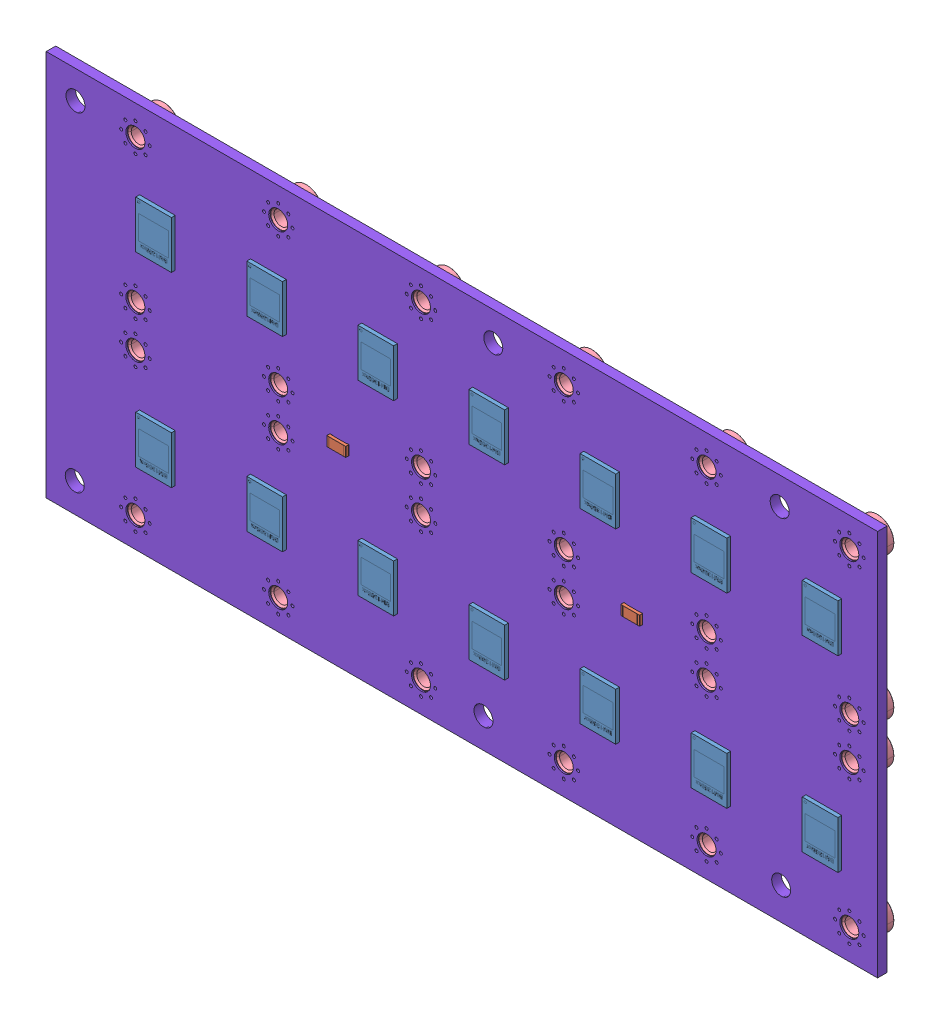
SolidWorks assembly EKO_Miner_AsicBoard-Template-01A, configuration Défaut. Lengths in mm.
Overall size (139.75 65 11.65).
104 component instances, 8 part files, 0 mates.
Components (placement in the parent):
- EKO_Miner_AsicBoard-Template-01A.step-1: EKO_Miner_AsicBoard-Template-01A.step [Défaut] at origin size (139.75 65 11.65)
  - BM1368xx.step-1: BM1368xx.step [Défaut] at (56.091 48.0498 1.65) x (-1 0 0) z (0 0 1) size (6 8 0.65)
    - BM1368PB.step-1: BM1368PB.step [Défaut] at origin size (6 8 0.65)
  - R_1206_3216Metric.step-1: R_1206_3216Metric.step [Défaut] at (49.348 32.465 1.65) size (3.2 1.6 0.55)
    - R_1206_3216Metric-0.step-1: R_1206_3216Metric-0.step [Défaut] at origin size (3.2 1.6 0.55)
  - BM1368xx.step-2: BM1368xx.step [Défaut] at (56.091 16.717 1.65) x (-1 0 0) z (0 0 1) size (6 8 0.65)
    - BM1368PB.step-1: BM1368PB.step [Défaut] at origin size (6 8 0.65)
  - BM1368xx.step-3: BM1368xx.step [Défaut] at (18.746 48.0498 1.65) x (-1 0 0) z (0 0 1) size (6 8 0.65)
    - BM1368PB.step-1: BM1368PB.step [Défaut] at origin size (6 8 0.65)
  - BM1368xx.step-4: BM1368xx.step [Défaut] at (93.436 16.717 1.65) x (-1 0 0) z (0 0 1) size (6 8 0.65)
    - BM1368PB.step-1: BM1368PB.step [Défaut] at origin size (6 8 0.65)
  - BM1368xx.step-5: BM1368xx.step [Défaut] at (93.436 48.0498 1.65) x (-1 0 0) z (0 0 1) size (6 8 0.65)
    - BM1368PB.step-1: BM1368PB.step [Défaut] at origin size (6 8 0.65)
  - BM1368xx.step-6: BM1368xx.step [Défaut] at (37.4185 48.0498 1.65) x (-1 0 0) z (0 0 1) size (6 8 0.65)
    - BM1368PB.step-1: BM1368PB.step [Défaut] at origin size (6 8 0.65)
  - BM1368xx.step-7: BM1368xx.step [Défaut] at (112.1085 48.0498 1.65) x (-1 0 0) z (0 0 1) size (6 8 0.65)
    - BM1368PB.step-1: BM1368PB.step [Défaut] at origin size (6 8 0.65)
  - BM1368xx.step-8: BM1368xx.step [Défaut] at (112.1085 16.717 1.65) x (-1 0 0) z (0 0 1) size (6 8 0.65)
    - BM1368PB.step-1: BM1368PB.step [Défaut] at origin size (6 8 0.65)
  - BM1368xx.step-9: BM1368xx.step [Défaut] at (74.7635 48.0498 1.65) x (-1 0 0) z (0 0 1) size (6 8 0.65)
    - BM1368PB.step-1: BM1368PB.step [Défaut] at origin size (6 8 0.65)
  - BM1368xx.step-10: BM1368xx.step [Défaut] at (37.4185 16.717 1.65) x (-1 0 0) z (0 0 1) size (6 8 0.65)
    - BM1368PB.step-1: BM1368PB.step [Défaut] at origin size (6 8 0.65)
  - BM1368xx.step-11: BM1368xx.step [Défaut] at (74.7635 16.717 1.65) x (-1 0 0) z (0 0 1) size (6 8 0.65)
    - BM1368PB.step-1: BM1368PB.step [Défaut] at origin size (6 8 0.65)
  - BM1368xx.step-12: BM1368xx.step [Défaut] at (18.746 16.717 1.65) x (-1 0 0) z (0 0 1) size (6 8 0.65)
    - BM1368PB.step-1: BM1368PB.step [Défaut] at origin size (6 8 0.65)
  - R_1206_3216Metric.step-2: R_1206_3216Metric.step [Défaut] at (98.751 32.592 1.65) size (3.2 1.6 0.55)
    - R_1206_3216Metric-0.step-1: R_1206_3216Metric-0.step [Défaut] at origin size (3.2 1.6 0.55)
  - BM1368xx.step-13: BM1368xx.step [Défaut] at (130.781 16.717 1.65) x (-1 0 0) z (0 0 1) size (6 8 0.65)
    - BM1368PB.step-1: BM1368PB.step [Défaut] at origin size (6 8 0.65)
  - BM1368xx.step-14: BM1368xx.step [Défaut] at (130.781 48.264 1.65) x (-1 0 0) z (0 0 1) size (6 8 0.65)
    - BM1368PB.step-1: BM1368PB.step [Défaut] at origin size (6 8 0.65)
  - C_0805_2012Metric.step-1: C_0805_2012Metric.step [Défaut] at (6.702 9.097 -0.05) x (-1 0 0) z (0 0 -1) size (2 1.25 1.25)
    - C_0805_2012Metric-0.step-1: C_0805_2012Metric-0.step [Défaut] at origin size (2 1.25 1.25)
  - SMTSO-M3-3ET.step-1: SMTSO-M3-3ET.step [Défaut] at (39 29 1.35) x (0 0 -1) z (1 0 0) size (4.53 5.56 5.56)
    - 1.step-1: 1.step [Défaut] at origin size (4.53 5.56 5.56)
  - SMTSO-M3-3ET.step-2: SMTSO-M3-3ET.step [Défaut] at (111 5 1.35) x (0 0 -1) z (1 0 0) size (4.53 5.56 5.56)
    - 1.step-1: 1.step [Défaut] at origin size (4.53 5.56 5.56)
  - SMTSO-M3-3ET.step-3: SMTSO-M3-3ET.step [Défaut] at (63 29 1.35) x (0 0 -1) z (1 0 0) size (4.53 5.56 5.56)
    - 1.step-1: 1.step [Défaut] at origin size (4.53 5.56 5.56)
  - SMTSO-M3-3ET.step-4: SMTSO-M3-3ET.step [Défaut] at (87 36 1.35) x (0 0 -1) z (1 0 0) size (4.53 5.56 5.56)
    - 1.step-1: 1.step [Défaut] at origin size (4.53 5.56 5.56)
  - SMTSO-M3-3ET.step-5: SMTSO-M3-3ET.step [Défaut] at (15 60 1.35) x (0 0 -1) z (1 0 0) size (4.53 5.56 5.56)
    - 1.step-1: 1.step [Défaut] at origin size (4.53 5.56 5.56)
  - PinHeader_2x04_P2.54mm_Vertical_SMD.step-1: PinHeader_2x04_P2.54mm_Vertical_SMD.step [Défaut] at (4.67 26.242 -0.05) x (1 0 0) z (0 0 -1) size (7.54 10.16 9.3)
    - PinHeader_2x04_P254mm_Vertical_SMD.step-1: PinHeader_2x04_P254mm_Vertical_SMD.step [Défaut] at origin size (7.54 10.16 9.3)
  - SMTSO-M3-3ET.step-6: SMTSO-M3-3ET.step [Défaut] at (135 5 1.35) x (0 0 -1) z (1 0 0) size (4.53 5.56 5.56)
    - 1.step-1: 1.step [Défaut] at origin size (4.53 5.56 5.56)
  - SMTSO-M3-3ET.step-7: SMTSO-M3-3ET.step [Défaut] at (63 60 1.35) x (0 0 -1) z (1 0 0) size (4.53 5.56 5.56)
    - 1.step-1: 1.step [Défaut] at origin size (4.53 5.56 5.56)
  - C_0805_2012Metric.step-2: C_0805_2012Metric.step [Défaut] at (6.829 55.6625 -0.05) x (-1 0 0) z (0 0 -1) size (2 1.25 1.25)
    - C_0805_2012Metric-0.step-1: C_0805_2012Metric-0.step [Défaut] at origin size (2 1.25 1.25)
  - SOT230P700X180-4N.step-1: SOT230P700X180-4N.step [Défaut] at (4.67 13.669 -0.05) x (-1 0 0) z (0 -1 0) size (7 1.8 6.5)
    - MIC39100-3.3WS-TR.step-1: MIC39100-3.3WS-TR.step [Défaut] at origin size (7 1.8 6.5)
  - SMTSO-M3-3ET.step-8: SMTSO-M3-3ET.step [Défaut] at (63 5 1.35) x (0 0 -1) z (1 0 0) size (4.53 5.56 5.56)
    - 1.step-1: 1.step [Défaut] at origin size (4.53 5.56 5.56)
  - R_0805_2012Metric.step-1: R_0805_2012Metric.step [Défaut] at (24.625 5.795 -0.05) x (-1 0 0) z (0 0 -1) size (2 1.2 0.45)
    - R_0805_2012Metric-3.step-1: R_0805_2012Metric-3.step [Défaut] at origin size (2 1.2 0.45)
  - SOT230P700X180-4N.step-2: SOT230P700X180-4N.step [Défaut] at (4.67 51.134 -0.05) x (-1 0 0) z (0 -1 0) size (7 1.8 6.5)
    - MIC39100-3.3WS-TR.step-1: MIC39100-3.3WS-TR.step [Défaut] at origin size (7 1.8 6.5)
  - SMTSO-M3-3ET.step-9: SMTSO-M3-3ET.step [Défaut] at (39 5 1.35) x (0 0 -1) z (1 0 0) size (4.53 5.56 5.56)
    - 1.step-1: 1.step [Défaut] at origin size (4.53 5.56 5.56)
  - SMTSO-M3-3ET.step-10: SMTSO-M3-3ET.step [Défaut] at (87 5 1.35) x (0 0 -1) z (1 0 0) size (4.53 5.56 5.56)
    - 1.step-1: 1.step [Défaut] at origin size (4.53 5.56 5.56)
  - SMTSO-M3-3ET.step-11: SMTSO-M3-3ET.step [Défaut] at (87 29 1.35) x (0 0 -1) z (1 0 0) size (4.53 5.56 5.56)
    - 1.step-1: 1.step [Défaut] at origin size (4.53 5.56 5.56)
  - C_0805_2012Metric.step-3: C_0805_2012Metric.step [Défaut] at (6.829 46.6455 -0.05) x (-1 0 0) z (0 0 -1) size (2 1.25 1.25)
    - C_0805_2012Metric-0.step-1: C_0805_2012Metric-0.step [Défaut] at origin size (2 1.25 1.25)
  - SMTSO-M3-3ET.step-12: SMTSO-M3-3ET.step [Défaut] at (111 36 1.35) x (0 0 -1) z (1 0 0) size (4.53 5.56 5.56)
    - 1.step-1: 1.step [Défaut] at origin size (4.53 5.56 5.56)
  - PinHeader_2x04_P2.54mm_Vertical_SMD.step-2: PinHeader_2x04_P2.54mm_Vertical_SMD.step [Défaut] at (4.67 39.958 -0.05) x (1 0 0) z (0 0 -1) size (7.54 10.16 9.3)
    - PinHeader_2x04_P254mm_Vertical_SMD.step-1: PinHeader_2x04_P254mm_Vertical_SMD.step [Défaut] at origin size (7.54 10.16 9.3)
  - SMTSO-M3-3ET.step-13: SMTSO-M3-3ET.step [Défaut] at (135 29 1.35) x (0 0 -1) z (1 0 0) size (4.53 5.56 5.56)
    - 1.step-1: 1.step [Défaut] at origin size (4.53 5.56 5.56)
  - SMTSO-M3-3ET.step-14: SMTSO-M3-3ET.step [Défaut] at (111 60 1.35) x (0 0 -1) z (1 0 0) size (4.53 5.56 5.56)
    - 1.step-1: 1.step [Défaut] at origin size (4.53 5.56 5.56)
  - R_0805_2012Metric.step-2: R_0805_2012Metric.step [Défaut] at (24.641 3.382 -0.05) x (-1 0 0) z (0 0 -1) size (2 1.2 0.45)
    - R_0805_2012Metric-3.step-1: R_0805_2012Metric-3.step [Défaut] at origin size (2 1.2 0.45)
  - SMTSO-M3-3ET.step-15: SMTSO-M3-3ET.step [Défaut] at (39 60 1.35) x (0 0 -1) z (1 0 0) size (4.53 5.56 5.56)
    - 1.step-1: 1.step [Défaut] at origin size (4.53 5.56 5.56)
  - SMTSO-M3-3ET.step-16: SMTSO-M3-3ET.step [Défaut] at (135 60 1.35) x (0 0 -1) z (1 0 0) size (4.53 5.56 5.56)
    - 1.step-1: 1.step [Défaut] at origin size (4.53 5.56 5.56)
  - SMTSO-M3-3ET.step-17: SMTSO-M3-3ET.step [Défaut] at (39 36 1.35) x (0 0 -1) z (1 0 0) size (4.53 5.56 5.56)
    - 1.step-1: 1.step [Défaut] at origin size (4.53 5.56 5.56)
  - SMTSO-M3-3ET.step-18: SMTSO-M3-3ET.step [Défaut] at (63 36 1.35) x (0 0 -1) z (1 0 0) size (4.53 5.56 5.56)
    - 1.step-1: 1.step [Défaut] at origin size (4.53 5.56 5.56)
  - SMTSO-M3-3ET.step-19: SMTSO-M3-3ET.step [Défaut] at (135 36 1.35) x (0 0 -1) z (1 0 0) size (4.53 5.56 5.56)
    - 1.step-1: 1.step [Défaut] at origin size (4.53 5.56 5.56)
  - SMTSO-M3-3ET.step-20: SMTSO-M3-3ET.step [Défaut] at (111 29 1.35) x (0 0 -1) z (1 0 0) size (4.53 5.56 5.56)
    - 1.step-1: 1.step [Défaut] at origin size (4.53 5.56 5.56)
  - SMTSO-M3-3ET.step-21: SMTSO-M3-3ET.step [Défaut] at (87 60 1.35) x (0 0 -1) z (1 0 0) size (4.53 5.56 5.56)
    - 1.step-1: 1.step [Défaut] at origin size (4.53 5.56 5.56)
  - SMTSO-M3-3ET.step-22: SMTSO-M3-3ET.step [Défaut] at (15 29 1.35) x (0 0 -1) z (1 0 0) size (4.53 5.56 5.56)
    - 1.step-1: 1.step [Défaut] at origin size (4.53 5.56 5.56)
  - SMTSO-M3-3ET.step-23: SMTSO-M3-3ET.step [Défaut] at (15 5 1.35) x (0 0 -1) z (1 0 0) size (4.53 5.56 5.56)
    - 1.step-1: 1.step [Défaut] at origin size (4.53 5.56 5.56)
  - SMTSO-M3-3ET.step-24: SMTSO-M3-3ET.step [Défaut] at (15 36 1.35) x (0 0 -1) z (1 0 0) size (4.53 5.56 5.56)
    - 1.step-1: 1.step [Défaut] at origin size (4.53 5.56 5.56)
  - C_0805_2012Metric.step-4: C_0805_2012Metric.step [Défaut] at (11.0415 51.134 -0.05) x (1 0 0) z (0 0 -1) size (2 1.25 1.25)
    - C_0805_2012Metric-0.step-1: C_0805_2012Metric-0.step [Défaut] at origin size (2 1.25 1.25)
  - C_0805_2012Metric.step-5: C_0805_2012Metric.step [Défaut] at (6.702 18.241 -0.05) x (-1 0 0) z (0 0 -1) size (2 1.25 1.25)
    - C_0805_2012Metric-0.step-1: C_0805_2012Metric-0.step [Défaut] at origin size (2 1.25 1.25)
  - EKO_Miner_AsicsBoard_Template_01A_PCB.step-1: EKO_Miner_AsicsBoard_Template_01A_PCB.step [Défaut] at origin size (139.75 65 1.6)
